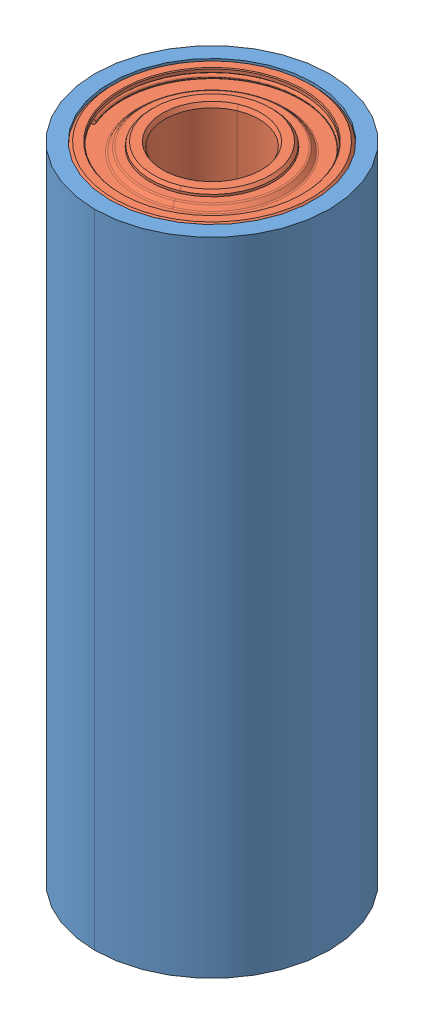
SolidWorks assembly 1607-0041-0615 assembly, configuration Default. Lengths in mm.
Overall size (17.04 41 17.04).
4 component instances, 2 part files, 0 mates.
Components (placement in the parent):
- 1607-0041-0615 assembly.STEP-1: 1607-0041-0615 assembly.STEP [Default] at origin size (17.04 41 17.04)
  - 1607-0041-0615.STEP-1: 1607-0041-0615.STEP [Default] at (-22.1413 9.5426 5.2006) size (15 41 15)
  - 1600-0513-0006.STEP-1: 1600-0513-0006.STEP [Default] at (-22.1413 25.0426 5.2006) x (0.920811 0 -0.39001) z (0.39001 0 0.920811) size (13 5 13)
  - 1600-0513-0006.STEP-2: 1600-0513-0006.STEP [Default] at (-22.1413 -10.9574 5.2006) x (0.948511 0 0.316745) z (-0.316745 0 0.948511) size (13 5 13)
